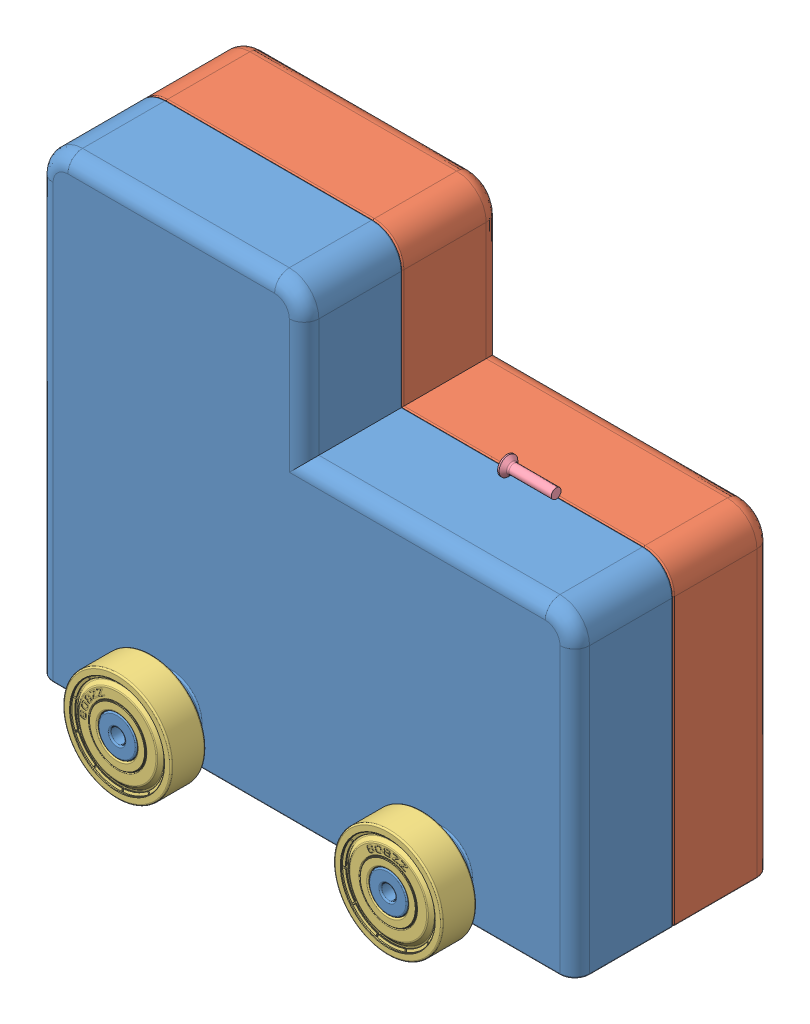
SolidWorks assembly Assemblage, configuration Défaut. Lengths in mm.
Overall size (109 101.44 62).
7 component instances, 5 part files, 6 mates.
Components (placement in the parent):
- coté droit de loco-1: coté droit de loco [Défaut] at (50.9994 21.5963 -18.5) size (109 94 31)
- Symétriecoté droite de loco-3: Symétriecoté droite de loco [Défaut] at (50.9994 21.5963 -18.5) size (109 94 35)
- Ball Bearing 608ZZ-2: Ball Bearing 608ZZ [Défaut] at (23.9994 -34.4037 9) x (0.61691 -0.787034 0) z (0 0 1) size (22 22 7)
- Ball Bearing 608ZZ-3: Ball Bearing 608ZZ [Défaut] at (-31.0006 -34.4037 9) x (0.997066 0.076552 0) z (0 0 1) size (22 22 7)
- Ball Bearing 608ZZ-4: Ball Bearing 608ZZ [Défaut] at (-5.0006 -34.4037 -46) x (-0.462558 -0.886589 0) z (0 0 -1) size (22 22 7)
- Pièce1^Assemblage-1: Pièce1^Assemblage [Défaut] at origin (virtual)
- countersunk raised head cross recess screw_iso-1: countersunk raised head cross recess screw_iso [ISO 7047 - M2 x 10 - Z - 10N] at (30.1524 35.4232 -5.0655) size (10.47 3.8 3.8)
Mates (geometry in assembly coordinates):
- Coaxiale6: concentric: cylinder of coté droit de loco-1 through (-31.0006 -34.4037 12.5) axis (0 0 -1) radius 4; cylinder of Ball Bearing 608ZZ-3 through (-31.0006 -34.4037 244.0503) axis (0 0 1) radius 4
- Coïncidente1: coincident: plane of coté droit de loco-1 through (-31.0006 -34.4037 12.5) normal (0 0 1); plane of Ball Bearing 608ZZ-3 through (-31.0006 -34.4037 12.5) normal (0 0 1)
- Coaxiale7: concentric: cylinder of coté droit de loco-1 through (23.9994 -34.4037 12.5) axis (0 0 -1) radius 4; cylinder of Ball Bearing 608ZZ-2 through (23.9994 -34.4037 244.0503) axis (0 0 1) radius 4
- Coïncidente2: coincident: plane of coté droit de loco-1 through (23.9994 -34.4037 12.5) normal (0 0 1); plane of Ball Bearing 608ZZ-2 through (23.9994 -34.4037 12.5) normal (0 0 1)
- Coaxiale9: concentric: cylinder of Symétriecoté droite de loco-3 through (-5.0006 -34.4037 -49.5) axis (0 0 1) radius 4; cylinder of Ball Bearing 608ZZ-4 through (-5.0006 -34.4037 -281.0503) axis (0 0 -1) radius 4
- Coïncidente5: coincident: plane of Symétriecoté droite de loco-3 through (-5.0006 -34.4037 -49.5) normal (0 0 -1); plane of Ball Bearing 608ZZ-4 through (-5.0006 -34.4037 -49.5) normal (0 0 -1)
